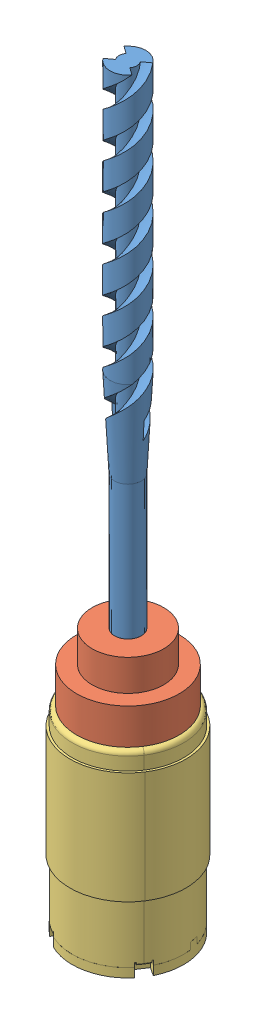
SolidWorks assembly drill, configuration Default. Lengths in mm.
Overall size (36.61 176.85 36.4).
3 component instances, 3 part files, 4 mates.
Components (placement in the parent):
- DRILL-1: DRILL [Default] at (-13.3618 16.1001 -28.7594) size (8.45 114.43 8.38)
- Drill connect-1: Drill connect [Default] at (-13.3618 223.5996 -28.7594) size (22.92 15 22.92)
- Medium motor-1: Medium motor [Default] at (-29.6887 221.7857 -28.4817) x (-0.832298 0.008789 -0.554259) z (0.007315 0.999961 0.004871) size (26.16 25.94 63.52)
Mates (geometry in assembly coordinates):
- Concentric1: concentric aligned: circle of DRILL-1; circle of Drill connect-1
- Coincident2: coincident aligned: circle of DRILL-1; circle of Drill connect-1
- Concentric2: concentric aligned: circle of Drill connect-1; circle of Medium motor-1
- Coincident3: coincident anti-aligned: plane of Drill connect-1 through (-13.3618 223.5996 -28.7594) normal (0 -1 0); plane of Medium motor-1 through (-13.3618 223.5996 -28.7594) normal (0 1 0)
